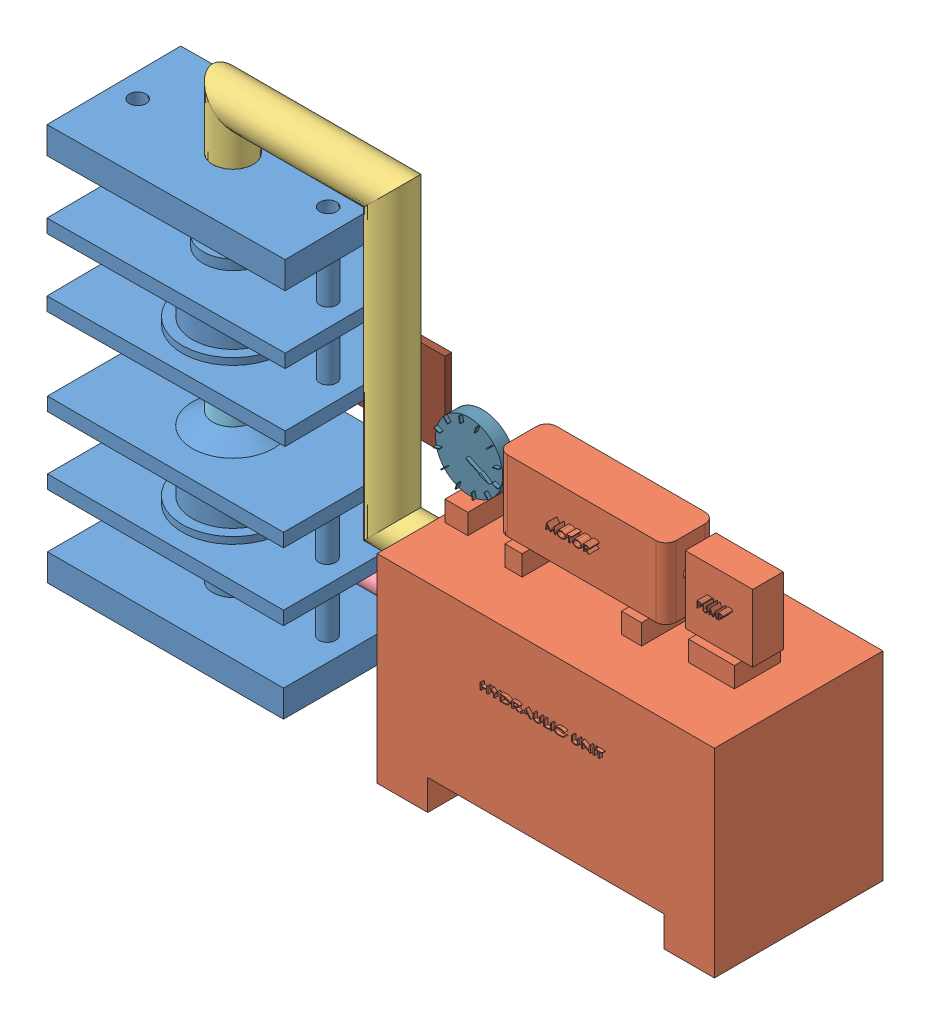
SolidWorks assembly 214103220, configuration Default. Lengths in mm.
Overall size (2047.71 1378.64 531.08).
19 component instances, 14 part files, 33 mates.
Components (placement in the parent):
- Hydraulic and MRPF Cylinders-1: Hydraulic and MRPF Cylinders [Default] at (317.9513 182.4691 616.1963) size (700 518.08 400)
- Hydraulic and MRPF Cylinders-2: Hydraulic and MRPF Cylinders [Default] at (317.9513 1282.0256 616.1963) x (-0.99996 0 0.008921) z (0.008921 0 0.99996) size (700 518.08 400)
- HYDRAULIC UNIT-1: HYDRAULIC UNIT [Default] at (1471.1661 232.3042 591.7131) size (1000 860 510)
- PIPELINE 1-1: PIPELINE 1 [Default] at (647.0253 1015.6185 616.1963) size (718.15 975.66 120)
- PIPELINE 2-1: PIPELINE 2 [Default] at (311.1661 261.945 430.3824) x (1 0 0) z (0 0.026838 -0.99964) size (695 70 215)
- Workpiece Holder-1: Workpiece Holder [Default] at (317.9513 653.9458 616.1963) x (-0.995871 0 -0.090778) z (0.090778 0 -0.995871) size (120 150 120)
- Workpiece fixture-1: Workpiece fixture [Default] at (317.9513 772.6766 616.1963) size (80 150 80)
- Workpiece-1: Workpiece [Default] at (317.9513 653.9458 616.1963) x (-0.747966 0 -0.663737) z (0.663737 0 -0.747966) size (18 135 18)
- Support of mounting-1: Support of mounting [Default] at (314.3596 746.2672 566.4916) x (-0.731755 0.681536 0.006528) z (-0.008921 0 -0.99996) size (60 60 64.9)
- hex finished bolt_ai-3: hex finished bolt_ai [HFBOLT 1.125-12x4x4-S] at (313.2895 746.2672 446.545) x (0.008921 0 0.99996) z (0.923691 -0.383049 -0.008241) size (119.84 49.51 42.88)
- Mounting Bracket-1: Mounting Bracket [Default] at (313.7806 778.2105 501.5942) x (-0.99996 0 0.008921) z (0.008921 0 0.99996) size (400 60 124.62)
- Electromagnet-1: Electromagnet [Default] at (73.4506 746.2672 359.113) x (0.99996 0 -0.008921) z (0.008921 0 0.99996) size (300 250 20)
- Electromagnet-2: Electromagnet [Default] at (553.994 746.2672 354.8259) x (-0.99996 0 0.008921) z (0.008921 0 0.99996) size (300 250 20)
- hex finished bolt_ai-4: hex finished bolt_ai [HFBOLT 1.125-12x3.5x2.5-S] at (174.091 746.2672 430.4553) x (-0.008921 0 -0.99996) z (0.99996 0 -0.008921) size (107.14 49.51 42.88)
- hex finished bolt_ai-5: hex finished bolt_ai [HFBOLT 1.125-12x3.5x2.5-S] at (454.6424 746.2672 427.9523) x (-0.008921 0 -0.99996) z (0.99996 0 -0.008921) size (107.14 49.51 42.88)
- hex nut_ai-1: hex nut_ai [HNUT 1.1250-12-D-S] at (173.4466 746.2672 358.2209) x (0.99996 0 -0.008921) z (0.008921 0 0.99996) size (42.88 49.51 25.37)
- hex nut_ai-2: hex nut_ai [HNUT 1.1250-12-D-S] at (453.9979 746.2672 355.718) x (0.99996 0 -0.008921) z (0.008921 0 0.99996) size (42.88 49.51 25.37)
- Part3-1: Part3 [Default] at (317.9513 142.4691 616.1963) x (0.405757 0 -0.913981) z (0.913981 0 0.405757) size (120 80 120)
- Pressure gauge-1: Pressure gauge [Default] at (1017.9153 892.3042 615.721) x (-0.977313 -0.211765 -0.003861) z (0.003951 0 -0.999992) size (200 200 50)
Mates (geometry in assembly coordinates):
- Concentric1: concentric anti-aligned: circle of Platform-1; circle of Platform-2
- Coincident6: coincident anti-aligned: circle of Platform-2; circle of PIPELINE 1-1
- Parallel1: parallel aligned: plane of Platform-1 through (317.9513 142.4691 616.1963) normal (0 -1 0); plane of HYDRAULIC CYLINDER-1 through (1471.1661 142.3042 591.7131) normal (0 -1 0)
- Parallel4: parallel anti-aligned: plane of HYDRAULIC CYLINDER-1 through (971.1661 732.3042 841.7131) normal (-1 0 0); plane of PIPELINE 1-1 through (976.0993 605.2907 616.1963) normal (1 0 0)
- Concentric2: concentric anti-aligned: cylinder of Workpiece Holder-1 through (317.9513 803.9458 616.1963) axis (0 -1 0) radius 50; cylinder of Workpiece fixture-1 through (317.9513 807.7579 616.1963) axis (0 1 0) radius 40
- Coincident15: coincident aligned: plane of Workpiece Holder-1 through (317.9513 653.9458 616.1963) normal (0 -1 0); plane of Workpiece fixture-1 through (329.9513 653.9458 616.1963) normal (0 -1 0)
- Concentric3: concentric anti-aligned: circle of Workpiece fixture-1; cylinder of Workpiece-1 through (317.9513 788.9458 616.1963) axis (0 -1 0) radius 9
- Coincident17: coincident aligned: plane of Workpiece fixture-1 through (329.9513 653.9458 616.1963) normal (0 -1 0); plane of Workpiece-1 through (317.9513 653.9458 616.1963) normal (0 -1 0)
- Coincident18: coincident anti-aligned: plane of Platform-2 through (267.9533 803.9458 616.6424) normal (0 -1 0); plane of Workpiece Holder-1 through (317.9513 803.9458 616.1963) normal (0 1 0)
- Coincident21: coincident anti-aligned: circle of Platform-2; circle of Workpiece Holder-1
- Concentric8: concentric anti-aligned: circle of Support of mounting-1; circle of hex finished bolt_ai-3
- Parallel5: parallel anti-aligned: plane of Platform-2 through (666.1532 842.0256 413.0819) normal (-0.008921 0 -0.99996); plane of Mounting Bracket-1 through (236.515 718.2105 411.6604) normal (0.008921 0 0.99996)
- Coincident32: coincident anti-aligned: plane of Support of mounting-1 through (313.7806 746.2672 501.5942) normal (-0.008921 0 -0.99996); plane of Mounting Bracket-1 through (397.3171 718.2105 500.8489) normal (0.008921 0 0.99996)
- Concentric9: concentric anti-aligned: circle of Support of mounting-1; circle of Mounting Bracket-1
- Coincident33: coincident anti-aligned: plane of hex finished bolt_ai-3 through (303.9705 723.4012 464.8661) normal (0.008921 0 0.99996); plane of Mounting Bracket-1 through (276.9934 718.2105 465.1068) normal (-0.008921 0 -0.99996)
- Concentric10: concentric anti-aligned: circle of Mounting Bracket-1; circle of Electromagnet-1
- Coincident34: coincident anti-aligned: plane of Mounting Bracket-1 through (116.2165 718.2105 378.7323) normal (-0.008921 0 -0.99996); plane of Electromagnet-1 through (73.629 746.2672 379.1123) normal (0.008921 0 0.99996)
- Concentric11: concentric aligned: circle of Mounting Bracket-1; circle of Electromagnet-2
- Coincident35: coincident anti-aligned: plane of Mounting Bracket-1 through (356.2069 718.2105 376.5912) normal (-0.008921 0 -0.99996); plane of Electromagnet-2 through (554.1724 746.2672 374.8251) normal (0.008921 0 0.99996)
- Concentric12: concentric aligned: circle of Mounting Bracket-1; circle of hex finished bolt_ai-4
- Coincident36: coincident anti-aligned: plane of Mounting Bracket-1 through (236.515 718.2105 411.6604) normal (0.008921 0 0.99996); plane of hex finished bolt_ai-4 through (173.9283 771.0212 412.2188) normal (-0.008921 0 -0.99996)
- Concentric13: concentric aligned: circle of Mounting Bracket-1; circle of hex finished bolt_ai-5
- Coincident38: coincident anti-aligned: plane of Mounting Bracket-1 through (516.5039 718.2105 409.1625) normal (0.008921 0 0.99996); plane of hex finished bolt_ai-5 through (454.4797 771.0212 409.7159) normal (-0.008921 0 -0.99996)
- Concentric14: concentric aligned: circle of hex finished bolt_ai-4; circle of hex nut_ai-1
- Coincident39: coincident anti-aligned: plane of Electromagnet-1 through (73.4506 746.2672 359.113) normal (-0.008921 0 -0.99996); plane of hex nut_ai-1 through (173.4466 771.0212 358.2209) normal (0.008921 0 0.99996)
- Concentric15: concentric aligned: circle of hex finished bolt_ai-5; circle of hex nut_ai-2
- Coincident40: coincident anti-aligned: plane of Electromagnet-2 through (553.994 746.2672 354.8259) normal (-0.008921 0 -0.99996); plane of hex nut_ai-2 through (453.9979 771.0212 355.718) normal (0.008921 0 0.99996)
- Concentric18: concentric aligned: circle of Platform-1; circle of Part3-1
- Coincident48: coincident aligned: plane of Platform-1 through (317.9513 142.4691 616.1963) normal (0 -1 0); plane of Part3-1 through (317.9513 142.4691 616.1963) normal (0 -1 0)
- Parallel6: parallel anti-aligned: plane of Platform-1 through (317.9513 622.4691 616.1963) normal (0 1 0); plane of Electromagnet-1 through (-76.365 621.2672 380.4504) normal (0 -1 0)
- Perpendicular1: perpendicular: plane of Platform-1 through (317.9513 622.4691 616.1963) normal (0 1 0); plane of Electromagnet-2 through (404.1783 871.2672 376.1633) normal (-0.99996 0 0.008921)
- Tangent2: tangent: circle of HYDRAULIC CYLINDER-1; cylinder of Pressure gauge-1 through (1018.0734 892.3042 575.7213) axis (-0.003951 0 0.999992) radius 100
- Tangent3: tangent anti-aligned: plane of HYDRAULIC CYLINDER-1 through (1471.1661 792.3042 591.7131) normal (0 1 0); cylinder of Pressure gauge-1 through (1018.0734 892.3042 575.7213) axis (-0.003951 0 0.999992) radius 100
